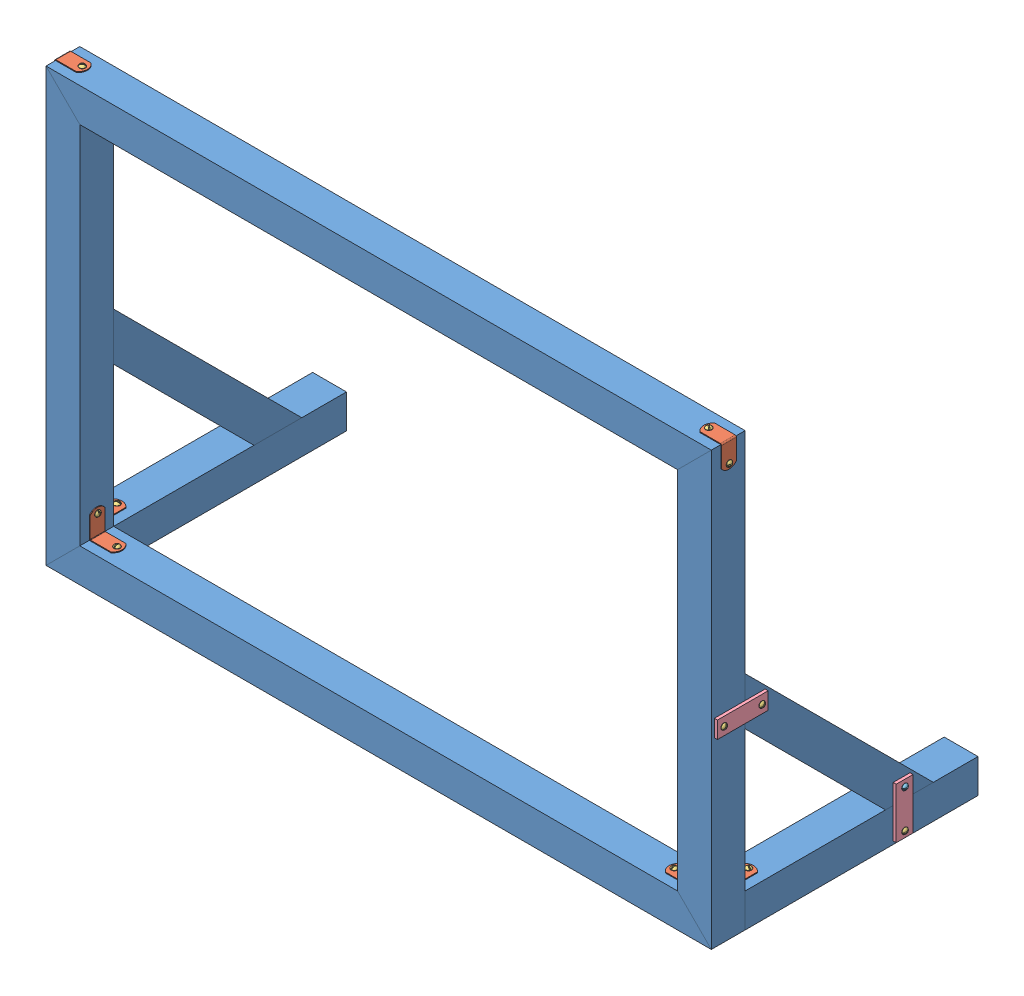
SolidWorks assembly Lumbar Support, configuration Default. Lengths in mm.
Overall size (1015.99 654.69 400.8).
38 component instances, 5 part files, 54 mates.
Components (placement in the parent):
- Lumbar supports-1: Lumbar supports [1000mm] at origin size (1000 50.8 50.8)
- Lumbar supports-2: Lumbar supports [650mm] at (474.6 -299.6 0) x (0 -1 0) z (0 0 1) size (650 50.8 50.8)
- Lumbar supports-3: Lumbar supports [1000mm] at (0 -599.2 0) x (1 0 0) z (0 0 -1) size (1000 50.8 50.8)
- Lumbar supports-4: Lumbar supports [650mm] at (-474.6 -299.6 0) x (0 -1 0) z (0 0 -1) size (650 50.8 50.8)
- Lumbar supports-5: Lumbar supports [400mm] at (-474.6 -450.3392 -148.8608) x (0 -0.707107 -0.707107) z (1 0 0) size (400 50.8 50.8)
- Lumbar supports-6: Lumbar supports [350 squared edge] at (-500 -599.2 -200.4) x (0 0 -1) z (1 0 0) size (350 50.8 50.8)
- Lumbar supports-9: Lumbar supports [350 squared edge] at (449.2 -599.2 -200.4) x (0 0 -1) z (1 0 0) size (350 50.8 50.8)
- Lumbar supports-11: Lumbar supports [400mm] at (474.6 -450.3392 -148.8608) x (0 -0.707107 -0.707107) z (1 0 0) size (400 50.8 50.8)
- 15705A450_BRACKET-1: 15705A450_BRACKET [15705A45] at (-501.27 26.67 0) x (1 0 0) z (0 -1 0) size (38.61 22.23 38.61)
- 92407A245_BRASS SLOTTED DECORATIVE ROUNDED HEAD SCREWS-1: 92407A245_BRASS SLOTTED DECORATIVE ROUNDED HEAD SCREWS [92407A245] at (-491.745 -3.81 0) size (22.47 9.12 9.12)
- 92407A245_BRASS SLOTTED DECORATIVE ROUNDED HEAD SCREWS-2: 92407A245_BRASS SLOTTED DECORATIVE ROUNDED HEAD SCREWS [92407A245] at (-470.79 17.145 0) x (0 -1 0) z (0.783204 0 -0.621764) size (22.47 9.12 9.12)
- 15705A450_BRACKET-3: 15705A450_BRACKET [15705A45] at (-449.2 -573.8 0) x (1 0 0) z (0 1 0) size (38.61 22.23 38.61)
- 92407A245_BRASS SLOTTED DECORATIVE ROUNDED HEAD SCREWS-4: 92407A245_BRASS SLOTTED DECORATIVE ROUNDED HEAD SCREWS [92407A245] at (-418.72 -582.055 0) x (0 -1 0) z (0.03324 0 0.999447) size (22.47 9.12 9.12)
- 92407A245_BRASS SLOTTED DECORATIVE ROUNDED HEAD SCREWS-6: 92407A245_BRASS SLOTTED DECORATIVE ROUNDED HEAD SCREWS [92407A245] at (-457.455 -543.32 0) x (-1 0 0) z (0 0.994504 0.104701) size (22.47 9.12 9.12)
- 15705A450_BRACKET-5: 15705A450_BRACKET [15705A45] at (-474.6 -573.8 -25.4) x (0 1 0) z (0 0 -1) size (38.61 22.23 38.61)
- 92407A245_BRASS SLOTTED DECORATIVE ROUNDED HEAD SCREWS-8: 92407A245_BRASS SLOTTED DECORATIVE ROUNDED HEAD SCREWS [92407A245] at (-474.6 -543.32 -17.145) x (0 0 1) z (-0.939693 -0.34202 0) size (22.47 9.12 9.12)
- 92407A245_BRASS SLOTTED DECORATIVE ROUNDED HEAD SCREWS-10: 92407A245_BRASS SLOTTED DECORATIVE ROUNDED HEAD SCREWS [92407A245] at (-474.6 -582.055 -55.88) x (0 -1 0) z (0.922096 0 -0.386961) size (22.47 9.12 9.12)
- 1030A400_BRACKET-1: 1030A400_BRACKET [1030A4] at (-500 -581.9 -260.5427) x (0 1 0) z (1 0 0) size (76.2 25.4 4.57)
- 92407A245_BRASS SLOTTED DECORATIVE ROUNDED HEAD SCREWS-12: 92407A245_BRASS SLOTTED DECORATIVE ROUNDED HEAD SCREWS [92407A245] at (-495.047 -553.325 -260.5427) x (1 0 0) z (0 -0.158553 0.987351) size (22.47 9.12 9.12)
- 92407A245_BRASS SLOTTED DECORATIVE ROUNDED HEAD SCREWS-14: 92407A245_BRASS SLOTTED DECORATIVE ROUNDED HEAD SCREWS [92407A245] at (-495.047 -610.475 -260.5427) x (1 0 0) z (0 -0.313094 0.949722) size (22.47 9.12 9.12)
- 1030A400_BRACKET-3: 1030A400_BRACKET [1030A4] at (-504.572 -338.6573 -17.3) x (0 0 -1) z (-1 0 0) size (76.2 25.4 4.57)
- 92407A245_BRASS SLOTTED DECORATIVE ROUNDED HEAD SCREWS-16: 92407A245_BRASS SLOTTED DECORATIVE ROUNDED HEAD SCREWS [92407A245] at (-495.047 -338.6573 -45.875) x (1 0 0) z (0 -0.66355 0.748132) size (22.47 9.12 9.12)
- 92407A245_BRASS SLOTTED DECORATIVE ROUNDED HEAD SCREWS-18: 92407A245_BRASS SLOTTED DECORATIVE ROUNDED HEAD SCREWS [92407A245] at (-495.047 -338.6573 11.275) x (1 0 0) z (0 -0.783381 0.621542) size (22.47 9.12 9.12)
- 1030A400_BRACKET-4: 1030A400_BRACKET [1030A4] at (504.572 -581.9 -260.5427) x (0 1 0) z (1 0 0) size (76.2 25.4 4.57)
- 92407A245_BRASS SLOTTED DECORATIVE ROUNDED HEAD SCREWS-20: 92407A245_BRASS SLOTTED DECORATIVE ROUNDED HEAD SCREWS [92407A245] at (474.6 -582.055 -55.88) x (0 -1 0) z (-0.922096 0 -0.386961) size (22.47 9.12 9.12)
- 15705A450_BRACKET-6: 15705A450_BRACKET [15705A45] at (474.6 -573.8 -25.4) x (0 1 0) z (0 0 -1) size (38.61 22.23 38.61)
- 15705A450_BRACKET-7: 15705A450_BRACKET [15705A45] at (449.2 -573.8 0) x (-1 0 0) z (0 1 0) size (38.61 22.23 38.61)
- 92407A245_BRASS SLOTTED DECORATIVE ROUNDED HEAD SCREWS-21: 92407A245_BRASS SLOTTED DECORATIVE ROUNDED HEAD SCREWS [92407A245] at (470.79 17.145 0) x (0 -1 0) z (-0.783204 0 -0.621764) size (22.47 9.12 9.12)
- 92407A245_BRASS SLOTTED DECORATIVE ROUNDED HEAD SCREWS-22: 92407A245_BRASS SLOTTED DECORATIVE ROUNDED HEAD SCREWS [92407A245] at (457.455 -543.32 0) x (1 0 0) z (0 -0.994504 -0.104701) size (22.47 9.12 9.12)
- 92407A245_BRASS SLOTTED DECORATIVE ROUNDED HEAD SCREWS-23: 92407A245_BRASS SLOTTED DECORATIVE ROUNDED HEAD SCREWS [92407A245] at (474.6 -543.32 -17.145) x (0 0 1) z (0.939693 -0.34202 0) size (22.47 9.12 9.12)
- 92407A245_BRASS SLOTTED DECORATIVE ROUNDED HEAD SCREWS-24: 92407A245_BRASS SLOTTED DECORATIVE ROUNDED HEAD SCREWS [92407A245] at (418.72 -582.055 0) x (0 -1 0) z (0.03324 0 -0.999447) size (22.47 9.12 9.12)
- 92407A245_BRASS SLOTTED DECORATIVE ROUNDED HEAD SCREWS-25: 92407A245_BRASS SLOTTED DECORATIVE ROUNDED HEAD SCREWS [92407A245] at (491.745 -3.81 0) x (-1 0 0) z (0 0 -1) size (22.47 9.12 9.12)
- 15705A450_BRACKET-8: 15705A450_BRACKET [15705A45] at (501.27 26.67 0) x (-1 0 0) z (0 -1 0) size (38.61 22.23 38.61)
- Mirror92407A245_BRASS SLOTTED DECORATIVE ROUNDED HEAD SCREWS-26: Mirror92407A245_BRASS SLOTTED DECORATIVE ROUNDED HEAD SCREWS [92407A245] at (495.047 -553.325 -260.5427) x (-1 0 0) z (0 0.158553 -0.987351) size (22.47 9.12 9.12)
- 1030A400_BRACKET-5: 1030A400_BRACKET [1030A4] at (500 -338.6573 -17.3) x (0 0 -1) z (-1 0 0) size (76.2 25.4 4.57)
- 92407A245_BRASS SLOTTED DECORATIVE ROUNDED HEAD SCREWS-26: 92407A245_BRASS SLOTTED DECORATIVE ROUNDED HEAD SCREWS [92407A245] at (495.047 -610.475 -260.5427) x (-1 0 0) z (0 0.313094 -0.949722) size (22.47 9.12 9.12)
- 92407A245_BRASS SLOTTED DECORATIVE ROUNDED HEAD SCREWS-27: 92407A245_BRASS SLOTTED DECORATIVE ROUNDED HEAD SCREWS [92407A245] at (495.047 -338.6573 -45.875) x (-1 0 0) z (0 0.66355 -0.748132) size (22.47 9.12 9.12)
- 92407A245_BRASS SLOTTED DECORATIVE ROUNDED HEAD SCREWS-28: 92407A245_BRASS SLOTTED DECORATIVE ROUNDED HEAD SCREWS [92407A245] at (495.047 -338.6573 11.275) x (-1 0 0) z (0 0.783381 -0.621542) size (22.47 9.12 9.12)
Mates (geometry in assembly coordinates):
- Coincident4: coincident aligned: plane of Lumbar supports-1 through (0 0 0) normal (0 1 0)
- Coincident5: coincident aligned: plane of Lumbar supports-1 through (0 0 0) normal (1 0 0)
- Coincident6: coincident aligned: plane of Lumbar supports-1 through (0 0 0) normal (0 0 1)
- ProfileCenter1: profile center anti-aligned: plane of Lumbar supports-2 through (324.8 -149.8 25.4) normal (-0.707107 0.707107 0); plane of Lumbar supports-1 through (237.3 -237.3 25.4) normal (0.707107 -0.707107 0)
- ProfileCenter2: profile center anti-aligned: plane of Lumbar supports-3 through (237.3 -361.9 -25.4) normal (0.707107 0.707107 0); plane of Lumbar supports-2 through (324.8 -449.4 25.4) normal (-0.707107 -0.707107 0)
- ProfileCenter3: profile center anti-aligned: plane of Lumbar supports-4 through (-324.8 -149.8 -25.4) normal (0.707107 0.707107 0); plane of Lumbar supports-1 through (-237.3 -237.3 25.4) normal (-0.707107 -0.707107 0)
- Coincident7: coincident anti-aligned: plane of Lumbar supports-4 through (-474.6 -299.6 -25.4) normal (0 0 -1); plane of Lumbar supports-5 through (-449.2 -450.3392 -25.4) normal (0 0 1)
- Coincident8: coincident aligned: plane of Lumbar supports-4 through (-500 -299.6 -25.4) normal (-1 0 0); plane of Lumbar supports-5 through (-500 -450.3392 -148.8608) normal (-1 0 0)
- Coincident10: coincident anti-aligned: plane of Lumbar supports-4 through (-474.6 -299.6 -25.4) normal (0 0 -1); plane of Lumbar supports-6 through (-449.2 -599.2 -25.4) normal (0 0 1)
- Coincident11: coincident aligned: plane of Lumbar supports-4 through (-500 -299.6 -25.4) normal (-1 0 0); plane of Lumbar supports-6 through (-500 -599.2 -200.4) normal (-1 0 0)
- Coincident12: coincident aligned: plane of Lumbar supports-3 through (0 -624.6 -25.4) normal (0 -1 0); plane of Lumbar supports-6 through (-449.2 -624.6 -200.4) normal (0 -1 0)
- Coincident13: coincident anti-aligned: plane of Lumbar supports-5 through (-449.2 -573.8 -148.8608) normal (0 -1 0); plane of Lumbar supports-6 through (-449.2 -573.8 -200.4) normal (0 1 0)
- Coincident20: coincident anti-aligned: plane of Lumbar supports-2 through (474.6 -299.6 -25.4) normal (0 0 -1); plane of Lumbar supports-9 through (500 -599.2 -25.4) normal (0 0 1)
- Coincident21: coincident aligned: plane of Lumbar supports-3 through (0 -624.6 -25.4) normal (0 -1 0); plane of Lumbar supports-9 through (500 -624.6 -200.4) normal (0 -1 0)
- Coincident22: coincident aligned: plane of Lumbar supports-2 through (500 -299.6 25.4) normal (1 0 0); plane of Lumbar supports-9 through (500 -599.2 -200.4) normal (1 0 0)
- Coincident27: coincident anti-aligned: plane of Lumbar supports-9 through (500 -573.8 -200.4) normal (0 1 0); plane of Lumbar supports-11 through (500 -573.8 -148.8608) normal (0 -1 0)
- Coincident28: coincident anti-aligned: plane of Lumbar supports-2 through (474.6 -299.6 -25.4) normal (0 0 -1); plane of Lumbar supports-11 through (500 -450.3392 -25.4) normal (0 0 1)
- Coincident29: coincident aligned: plane of Lumbar supports-2 through (500 -299.6 25.4) normal (1 0 0); plane of Lumbar supports-11 through (500 -450.3392 -148.8608) normal (1 0 0)
- Coincident30: coincident anti-aligned: plane of Lumbar supports-1 through (0 25.4 25.4) normal (0 1 0); plane of 15705A450_BRACKET-1 through (-499.365 25.4 11.1125) normal (0 -1 0)
- Width1: width anti-aligned: plane of 15705A450_BRACKET-1 through (-499.365 24.765 11.1125) normal (0 0 1); plane of Lumbar supports-1 through (-499.365 24.765 -11.1125) normal (0 0 -1); plane of 15705A450_BRACKET-1 through (0 0 -25.4) normal (0 0 -1); plane of Lumbar supports-1 through (0 0 25.4) normal (0 0 1)
- Coincident31: coincident anti-aligned: plane of Lumbar supports-4 through (-500 -299.6 -25.4) normal (-1 0 0); plane of 15705A450_BRACKET-1 through (-500 -11.43 11.1125) normal (1 0 0)
- Concentric1: concentric anti-aligned: cylinder of 15705A450_BRACKET-1 through (-501.27 -3.81 0) axis (1 0 0) radius 2.413; cylinder of 92407A245_BRASS SLOTTED DECORATIVE ROUNDED HEAD SCREWS-1 through (-504.7498 -3.81 0) axis (-1 0 0) radius 2.413
- Coincident32: coincident anti-aligned: plane of 15705A450_BRACKET-1 through (-501.27 -11.43 11.1125) normal (-1 0 0); plane of 92407A245_BRASS SLOTTED DECORATIVE ROUNDED HEAD SCREWS-1 through (-501.27 -1.397 0) normal (1 0 0)
- Concentric2: concentric aligned: cylinder of 15705A450_BRACKET-1 through (-470.79 -11.43 0) axis (0 1 0) radius 2.413; cylinder of 92407A245_BRASS SLOTTED DECORATIVE ROUNDED HEAD SCREWS-2 through (-470.79 30.1498 0) axis (0 1 0) radius 2.413
- Coincident33: coincident anti-aligned: plane of 15705A450_BRACKET-1 through (-499.365 26.67 11.1125) normal (0 1 0); plane of 92407A245_BRASS SLOTTED DECORATIVE ROUNDED HEAD SCREWS-2 through (-472.2903 26.67 -1.8899) normal (0 -1 0)
- Coincident36: coincident anti-aligned: plane of Lumbar supports-3 through (0 -573.8 -25.4) normal (0 1 0); plane of 15705A450_BRACKET-3 through (-447.295 -573.8 -11.1125) normal (0 -1 0)
- Coincident37: coincident anti-aligned: plane of Lumbar supports-4 through (-449.2 -299.6 -25.4) normal (1 0 0); plane of 15705A450_BRACKET-3 through (-449.2 -535.7 -11.1125) normal (-1 0 0)
- Width3: width anti-aligned: plane of 15705A450_BRACKET-3 through (-447.295 -571.895 11.1125) normal (0 0 1); plane of Lumbar supports-3 through (-447.295 -571.895 -11.1125) normal (0 0 -1); plane of 15705A450_BRACKET-3 through (0 -599.2 -25.4) normal (0 0 -1); plane of Lumbar supports-3 through (0 -599.2 25.4) normal (0 0 1)
- Concentric3: concentric anti-aligned: cylinder of 15705A450_BRACKET-3 through (-418.72 -535.7 0) axis (0 -1 0) radius 2.413; cylinder of 92407A245_BRASS SLOTTED DECORATIVE ROUNDED HEAD SCREWS-4 through (-418.72 -569.0502 0) axis (0 1 0) radius 2.413
- Coincident38: coincident anti-aligned: plane of 15705A450_BRACKET-3 through (-447.295 -572.53 -11.1125) normal (0 1 0); plane of 92407A245_BRASS SLOTTED DECORATIVE ROUNDED HEAD SCREWS-4 through (-416.3083 -572.53 -0.0802) normal (0 -1 0)
- Concentric4: concentric aligned: cylinder of 15705A450_BRACKET-3 through (-449.2 -543.32 0) axis (1 0 0) radius 2.413; cylinder of 92407A245_BRASS SLOTTED DECORATIVE ROUNDED HEAD SCREWS-6 through (-444.4502 -543.32 0) axis (1 0 0) radius 2.413
- Coincident39: coincident anti-aligned: plane of 15705A450_BRACKET-3 through (-447.93 -535.7 -11.1125) normal (1 0 0); plane of 92407A245_BRASS SLOTTED DECORATIVE ROUNDED HEAD SCREWS-6 through (-447.93 -543.5726 2.3997) normal (-1 0 0)
- Coincident42: coincident anti-aligned: plane of Lumbar supports-6 through (-449.2 -573.8 -200.4) normal (0 1 0); plane of 15705A450_BRACKET-5 through (-463.4875 -573.8 -63.5) normal (0 -1 0)
- Coincident43: coincident anti-aligned: plane of Lumbar supports-4 through (-474.6 -299.6 -25.4) normal (0 0 -1); plane of 15705A450_BRACKET-5 through (-463.4875 -571.895 -25.4) normal (0 0 1)
- Width7: width anti-aligned: plane of 15705A450_BRACKET-5 through (-485.7125 -571.895 -27.305) normal (-1 0 0); plane of Lumbar supports-6 through (-463.4875 -571.895 -27.305) normal (1 0 0); plane of 15705A450_BRACKET-5 through (-449.2 -599.2 -200.4) normal (1 0 0); plane of Lumbar supports-6 through (-500 -599.2 -200.4) normal (-1 0 0)
- Concentric5: concentric anti-aligned: cylinder of 15705A450_BRACKET-5 through (-474.6 -543.32 -63.5) axis (0 0 1) radius 2.413; cylinder of 92407A245_BRASS SLOTTED DECORATIVE ROUNDED HEAD SCREWS-8 through (-474.6 -543.32 -30.1498) axis (0 0 -1) radius 2.413
- Coincident44: coincident anti-aligned: plane of 15705A450_BRACKET-5 through (-463.4875 -571.895 -26.67) normal (0 0 -1); plane of 92407A245_BRASS SLOTTED DECORATIVE ROUNDED HEAD SCREWS-8 through (-475.4253 -541.0525 -26.67) normal (0 0 1)
- Concentric6: concentric aligned: cylinder of 15705A450_BRACKET-5 through (-474.6 -573.8 -55.88) axis (0 1 0) radius 2.413; cylinder of 92407A245_BRASS SLOTTED DECORATIVE ROUNDED HEAD SCREWS-10 through (-474.6 -569.0502 -55.88) axis (0 1 0) radius 2.413
- Coincident45: coincident anti-aligned: plane of 15705A450_BRACKET-5 through (-463.4875 -572.53 -63.5) normal (0 1 0); plane of 92407A245_BRASS SLOTTED DECORATIVE ROUNDED HEAD SCREWS-10 through (-475.5337 -572.53 -58.105) normal (0 -1 0)
- Coincident47: coincident anti-aligned: plane of Lumbar supports-5 through (-500 -450.3392 -148.8608) normal (-1 0 0); plane of 1030A400_BRACKET-1 through (-500 -620 -273.2427) normal (1 0 0)
- Distance1: distance = 30 mm aligned: plane of 1030A400_BRACKET-1 through (-504.572 -543.8 -247.8427) normal (0 1 0); plane of Lumbar supports-6 through (-449.2 -573.8 -200.4) normal (0 1 0)
- Distance2: distance = 35 mm: plane of 1030A400_BRACKET-1 through (-504.572 -620 -273.2427) normal (0 0 -1); line of Lumbar supports-5 through (-449.2 -573.8 -308.2427) axis (-1 0 0)
- Concentric7: concentric anti-aligned: cylinder of 1030A400_BRACKET-1 through (-504.572 -553.325 -260.5427) axis (1 0 0) radius 3.175; cylinder of 92407A245_BRASS SLOTTED DECORATIVE ROUNDED HEAD SCREWS-12 through (-508.0518 -553.325 -260.5427) axis (-1 0 0) radius 2.413
- Coincident50: coincident anti-aligned: plane of 1030A400_BRACKET-1 through (-504.572 -620 -273.2427) normal (-1 0 0); plane of 92407A245_BRASS SLOTTED DECORATIVE ROUNDED HEAD SCREWS-12 through (-504.572 -550.9425 -260.1601) normal (1 0 0)
- Concentric8: concentric anti-aligned: cylinder of 1030A400_BRACKET-1 through (-504.572 -610.475 -260.5427) axis (1 0 0) radius 3.175; cylinder of 92407A245_BRASS SLOTTED DECORATIVE ROUNDED HEAD SCREWS-14 through (-508.0518 -610.475 -260.5427) axis (-1 0 0) radius 2.413
- Coincident51: coincident anti-aligned: plane of 1030A400_BRACKET-1 through (-504.572 -620 -273.2427) normal (-1 0 0); plane of 92407A245_BRASS SLOTTED DECORATIVE ROUNDED HEAD SCREWS-14 through (-504.572 -608.1833 -259.7872) normal (1 0 0)
- Coincident53: coincident anti-aligned: plane of Lumbar supports-4 through (-500 -299.6 -25.4) normal (-1 0 0); plane of 1030A400_BRACKET-3 through (-500 -325.9573 20.8) normal (1 0 0)
- Parallel2: parallel aligned: plane of Lumbar supports-3 through (0 -624.6 -25.4) normal (0 -1 0); plane of 1030A400_BRACKET-3 through (-500 -351.3573 20.8) normal (0 -1 0)
- Distance4: distance = 30 mm aligned: plane of 1030A400_BRACKET-3 through (-500 -351.3573 -55.4) normal (0 0 -1); plane of Lumbar supports-4 through (-474.6 -299.6 -25.4) normal (0 0 -1)
- Distance5: distance = 35 mm: plane of 1030A400_BRACKET-3 through (-500 -325.9573 20.8) normal (0 1 0); line of Lumbar supports-5 through (-449.2 -290.9573 -25.4) axis (-1 0 0)
- Concentric9: concentric aligned: cylinder of 1030A400_BRACKET-3 through (-500 -338.6573 -45.875) axis (-1 0 0) radius 3.175; cylinder of 92407A245_BRASS SLOTTED DECORATIVE ROUNDED HEAD SCREWS-16 through (-508.0518 -338.6573 -45.875) axis (-1 0 0) radius 2.413
- Coincident58: coincident anti-aligned: plane of 1030A400_BRACKET-3 through (-504.572 -325.9573 20.8) normal (-1 0 0); plane of 92407A245_BRASS SLOTTED DECORATIVE ROUNDED HEAD SCREWS-16 through (-504.572 -336.852 -44.2739) normal (1 0 0)
- Concentric10: concentric aligned: cylinder of 1030A400_BRACKET-3 through (-500 -338.6573 11.275) axis (-1 0 0) radius 3.175; cylinder of 92407A245_BRASS SLOTTED DECORATIVE ROUNDED HEAD SCREWS-18 through (-508.0518 -338.6573 11.275) axis (-1 0 0) radius 2.413
- Coincident59: coincident anti-aligned: plane of 1030A400_BRACKET-3 through (-504.572 -325.9573 20.8) normal (-1 0 0); plane of 92407A245_BRASS SLOTTED DECORATIVE ROUNDED HEAD SCREWS-18 through (-504.572 -337.1575 13.1653) normal (1 0 0)
